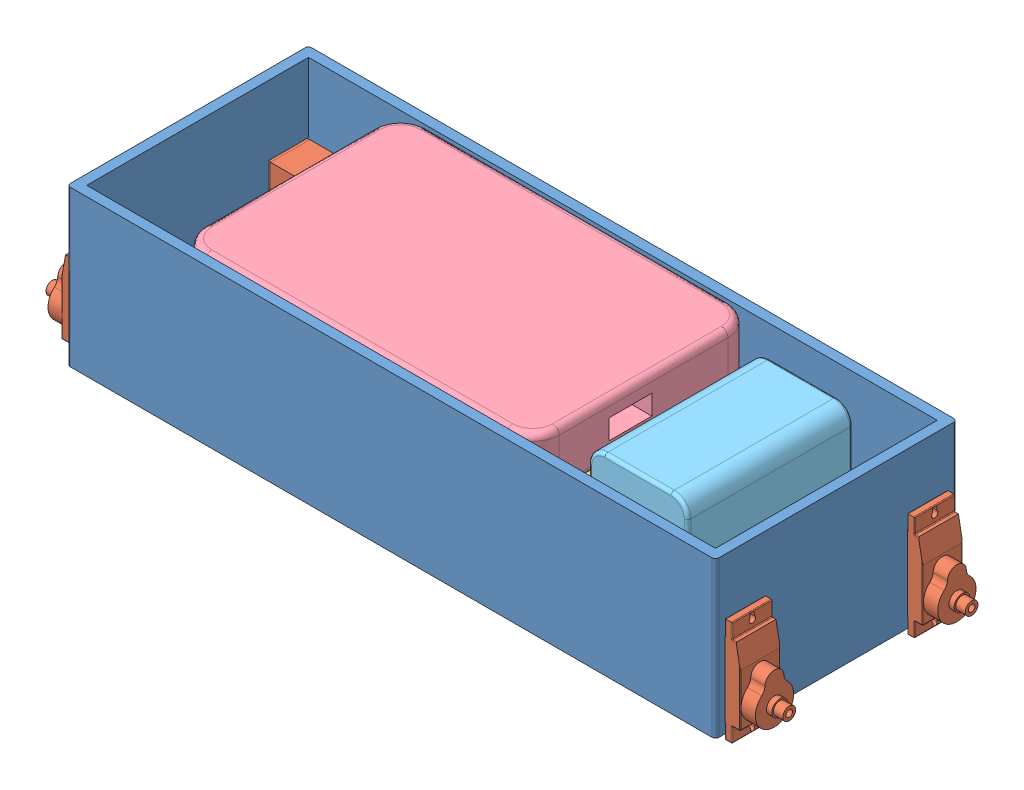
SolidWorks assembly Assem3, configuration Default. Lengths in mm.
Overall size (222.8 48.51 73).
8 component instances, 5 part files, 16 mates.
Components (placement in the parent):
- body encloser v1-1: body encloser v1 [Default] at (-21.4131 100.8483 201.3276) size (196 47 73)
- SERVO MG92B-1: SERVO MG92B [Predeterminado] at (154.0569 115.1833 192.4476) x (0 -1 0) z (0 0 1) size (31.69 33.93 12.06)
- SERVO MG92B-2: SERVO MG92B [Predeterminado] at (154.0569 115.1833 137.3276) x (0 -1 0) z (0 0 1) size (31.69 33.93 12.06)
- SERVO MG92B-3: SERVO MG92B [Predeterminado] at (-0.8831 115.1833 192.3276) x (0 -1 0) z (0 0 -1) size (31.69 33.93 12.06)
- SERVO MG92B-4: SERVO MG92B [Predeterminado] at (-0.8831 115.1833 137.2076) x (0 -1 0) z (0 0 -1) size (31.69 33.93 12.06)
- arduino with shild-1: arduino with shild [Default] at (61.6039 103.8483 194.6096) size (120 27 60)
- power bank-1: power bank [Default] at (62.8597 130.8483 198.3276) size (107 17 67)
- 9v battery-1: 9v battery [Default] at (123.1552 103.8483 163.3272) x (1 0 0) z (0 -1 0) size (30 50 42)
Mates (geometry in assembly coordinates):
- Coincident1: coincident anti-aligned: plane of body encloser v1-1 through (-18.4131 147.8483 198.3276) normal (0 0 -1); plane of SERVO MG92B-1 through (154.0569 115.1833 198.3276) normal (0 0 1)
- Coincident2: coincident anti-aligned: plane of body encloser v1-1 through (-21.4131 103.8483 201.3276) normal (0 1 0); plane of SERVO MG92B-1 through (156.8118 103.8483 186.4476) normal (0 -1 0)
- Coincident3: coincident anti-aligned: plane of body encloser v1-1 through (174.5869 103.8483 201.3276) normal (1 0 0); plane of SERVO MG92B-1 through (174.5869 131.0283 186.4176) normal (-1 0 0)
- Coincident4: coincident anti-aligned: plane of body encloser v1-1 through (-18.4131 147.8483 131.3276) normal (0 0 1); plane of SERVO MG92B-2 through (154.0569 115.1833 131.3276) normal (0 0 -1)
- Coincident5: coincident anti-aligned: plane of body encloser v1-1 through (-21.4131 103.8483 201.3276) normal (0 1 0); plane of SERVO MG92B-2 through (156.8118 103.8483 131.3276) normal (0 -1 0)
- Coincident6: coincident anti-aligned: plane of body encloser v1-1 through (174.5869 103.8483 201.3276) normal (1 0 0); plane of SERVO MG92B-2 through (174.5869 131.0283 131.2976) normal (-1 0 0)
- Coincident7: coincident anti-aligned: plane of body encloser v1-1 through (-18.4131 147.8483 198.3276) normal (0 0 -1); plane of SERVO MG92B-3 through (-0.8831 115.1833 198.3276) normal (0 0 1)
- Coincident8: coincident anti-aligned: plane of body encloser v1-1 through (-21.4131 103.8483 201.3276) normal (0 1 0); plane of SERVO MG92B-3 through (-3.6379 103.8483 198.3276) normal (0 -1 0)
- Coincident9: coincident anti-aligned: plane of body encloser v1-1 through (-21.4131 103.8483 201.3276) normal (-1 0 0); plane of SERVO MG92B-3 through (-21.4131 131.0283 198.3576) normal (1 0 0)
- Coincident10: coincident anti-aligned: plane of body encloser v1-1 through (-18.4131 147.8483 131.3276) normal (0 0 1); plane of SERVO MG92B-4 through (-0.8831 115.1833 131.3276) normal (0 0 -1)
- Coincident11: coincident anti-aligned: plane of body encloser v1-1 through (-21.4131 103.8483 201.3276) normal (0 1 0); plane of SERVO MG92B-4 through (-3.6379 103.8483 143.2076) normal (0 -1 0)
- Coincident12: coincident anti-aligned: plane of body encloser v1-1 through (-21.4131 103.8483 201.3276) normal (-1 0 0); plane of SERVO MG92B-4 through (-21.4131 131.0283 143.2376) normal (1 0 0)
- Coincident13: coincident anti-aligned: plane of body encloser v1-1 through (-21.4131 103.8483 201.3276) normal (0 1 0); plane of arduino with shild-1 through (121.6039 103.8483 194.6096) normal (0 -1 0)
- Coincident16: coincident anti-aligned: plane of body encloser v1-1 through (-21.4131 103.8483 201.3276) normal (0 1 0); plane of 9v battery-1 through (122.703 103.8483 189.9098) normal (0 -1 0)
- Coincident17: coincident anti-aligned: plane of arduino with shild-1 through (121.6039 130.8483 194.6096) normal (0 1 0); plane of power bank-1 through (116.3597 130.8483 206.5195) normal (0 -1 0)
- Coincident18: coincident anti-aligned: plane of body encloser v1-1 through (-18.4131 147.8483 131.3276) normal (0 0 1); plane of power bank-1 through (116.3597 130.8483 131.3276) normal (0 0 -1)
